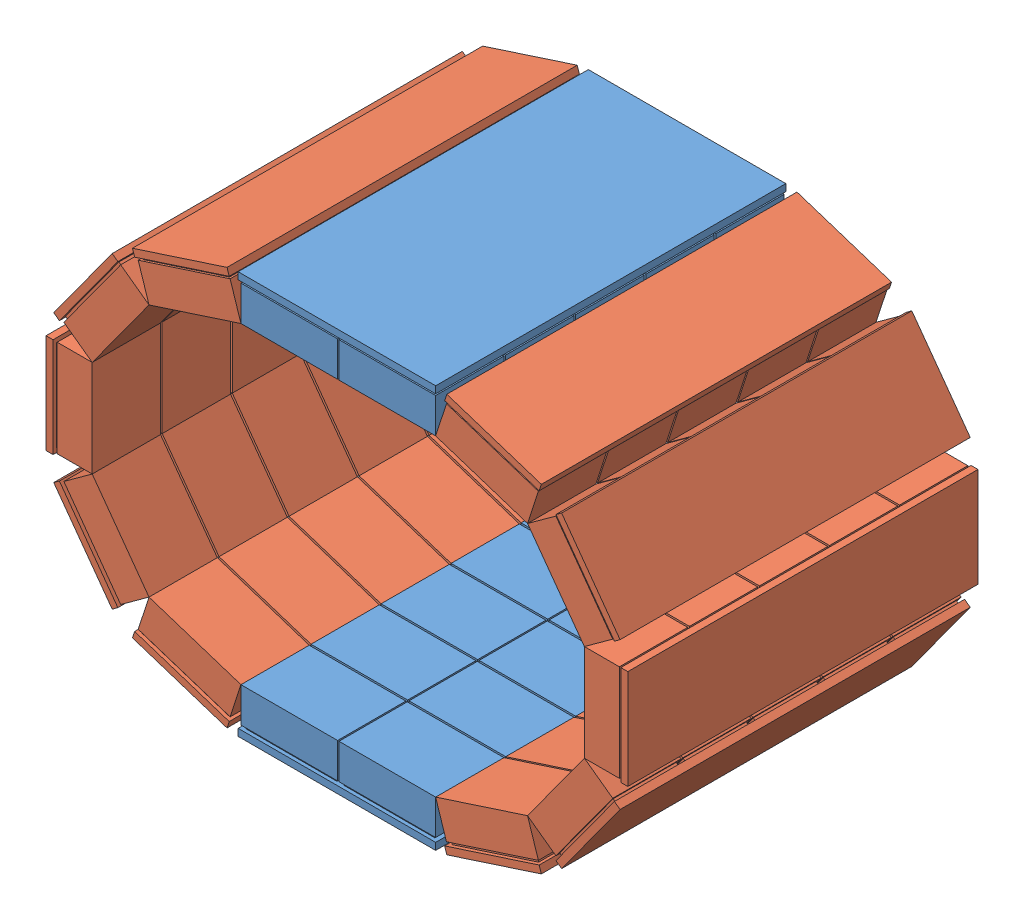
SolidWorks assembly Detector1, configuration Default. Lengths in mm.
Overall size (495.24 340.33 250).
14 component instances, 2 part files, 9 mates.
Components (placement in the parent):
- top_bottomDetector-1: top_bottomDetector [Default] at (86.8452 103.3776 184.3748) size (141 32 250)
- CshapedDetector-1: CshapedDetector [Default] at (185.8864 -33.4141 0.115) x (0.951057 0.309017 0) z (0 0 1) size (177.89 270.84 250)
  - 1Detector-1: 1Detector [Default] at (91.8512 126.8436 184.2598) size (71 32 250)
  - 1Detector-2: 1Detector [Default] at (173.0714 153.2337 184.2598) x (0.809017 0.587785 0) z (0 0 1) size (71 32 250)
  - 1Detector-4: 1Detector [Default] at (223.2683 222.3237 184.2598) x (0.309017 0.951057 0) z (0 0 1) size (71 32 250)
  - 1Detector-5: 1Detector [Default] at (223.2683 307.7237 184.2598) x (-0.309017 0.951057 0) z (0 0 1) size (71 32 250)
  - 1Detector-6: 1Detector [Default] at (173.0714 376.8138 184.2598) x (-0.809017 0.587785 0) z (0 0 1) size (71 32 250)
- CshapedDetector-2: CshapedDetector [Default] at (57.8041 527.4581 0.115) x (-0.951057 -0.309017 0) z (0 0 1) size (177.89 270.84 250)
  - 1Detector-1: 1Detector [Default] at (91.8512 126.8436 184.2598) size (71 32 250)
  - 1Detector-2: 1Detector [Default] at (173.0714 153.2337 184.2598) x (0.809017 0.587785 0) z (0 0 1) size (71 32 250)
  - 1Detector-4: 1Detector [Default] at (223.2683 222.3237 184.2598) x (0.309017 0.951057 0) z (0 0 1) size (71 32 250)
  - 1Detector-5: 1Detector [Default] at (223.2683 307.7237 184.2598) x (-0.309017 0.951057 0) z (0 0 1) size (71 32 250)
  - 1Detector-6: 1Detector [Default] at (173.0714 376.8138 184.2598) x (-0.809017 0.587785 0) z (0 0 1) size (71 32 250)
- top_bottomDetector-2: top_bottomDetector [Default] at (156.8452 390.6663 184.3748) x (-1 0 0) z (0 0 1) size (141 32 250)
Mates (geometry in assembly coordinates):
- Coincident1: coincident anti-aligned: line of top_bottomDetector-1 through (191.3452 135.3776 308.3872) axis (0 0 -1); line of CshapedDetector-1/1Detector-1 through (191.3452 135.3776 259.6324) axis (0 0 1)
- Angle1: planar angle = 3.455752 rad anti-aligned: line of top_bottomDetector-1 through (122.3452 135.3776 308.3872) axis (1 0 0); line of CshapedDetector-1/1Detector-1 through (191.3452 135.3776 308.3872) axis (0.951057 0.309017 0)
- Coincident3: coincident: point of top_bottomDetector-1; point of CshapedDetector-1/1Detector-1
- Coincident4: coincident anti-aligned: line of top_bottomDetector-1 through (52.3452 135.3776 259.6324) axis (0 0 1); line of CshapedDetector-2/1Detector-6 through (52.3452 135.3776 308.3872) axis (0 0 -1)
- Angle2: planar angle = 2.827433 rad anti-aligned: line of CshapedDetector-2/1Detector-6 through (-13.2777 156.6998 308.3872) axis (0.951057 -0.309017 0); line of top_bottomDetector-1 through (52.3452 135.3776 308.3872) axis (1 0 0)
- Coincident6: coincident: point of top_bottomDetector-1; point of CshapedDetector-2/1Detector-6
- Coincident7: coincident: line of CshapedDetector-1/1Detector-6 through (191.3452 358.6663 308.3872) axis (0 0 -1); line of top_bottomDetector-2 through (191.3452 358.6663 259.6324) axis (0 0 1)
- Coincident9: coincident: line of CshapedDetector-2/1Detector-1 through (52.3452 358.6663 259.6324) axis (0 0 1); line of top_bottomDetector-2 through (52.3452 358.6663 308.3872) axis (0 0 -1)
- Coincident10: coincident: point of CshapedDetector-2/1Detector-1; point of top_bottomDetector-2
